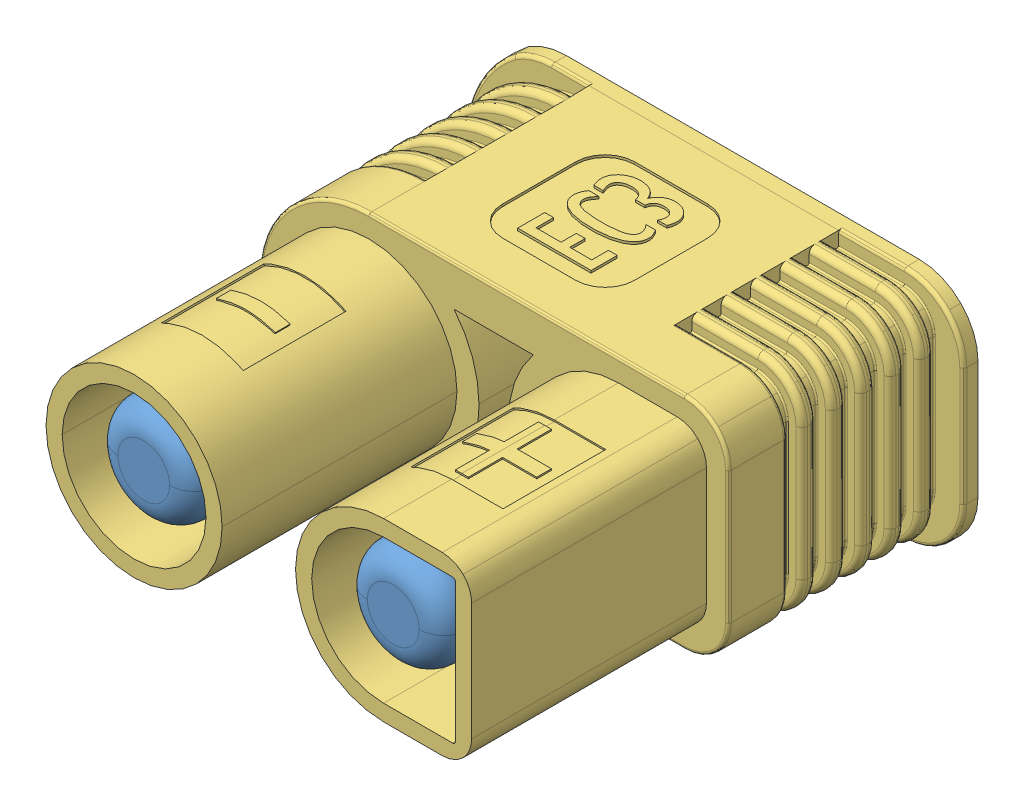
SolidWorks assembly EC3 Connector Plug, configuration Default. Lengths in mm.
Overall size (17 8.32 16).
11 component instances, 3 part files, 0 mates.
Components (placement in the parent):
- EC3 Connector Plug.stp-1: EC3 Connector Plug.stp [Default] at origin size (17 8.32 16)
  - EC3 Connector Assembly.stp-1: EC3 Connector Assembly.stp [Default] at origin size (17 8.32 16)
    - Plug.stp-1: Plug.stp [Default] at (-17.6267 -0.0297 -12.35) size (4.75 4.75 12.54)
      - 3-5mm Bullit Plug.stp-1: 3-5mm Bullit Plug.stp [Default] at origin size (4.75 4.75 12.54)
        - Pin.stp-1: Pin.stp [Default] at origin size (4.75 4.75 12.54)
        - Spring.stp-1: Spring.stp [Default] at origin size (4.11 4.11 5.4)
    - Plug.stp-2: Plug.stp [Default] at (-26.1267 -0.0297 -12.35) size (4.75 4.75 12.54)
      - 3-5mm Bullit Plug.stp-1: 3-5mm Bullit Plug.stp [Default] at origin size (4.75 4.75 12.54)
        - Pin.stp-1: Pin.stp [Default] at origin size (4.75 4.75 12.54)
        - Spring.stp-1: Spring.stp [Default] at origin size (4.11 4.11 5.4)
    - Shell2.stp-1: Shell2.stp [Default] at origin size (17 8.32 16)
